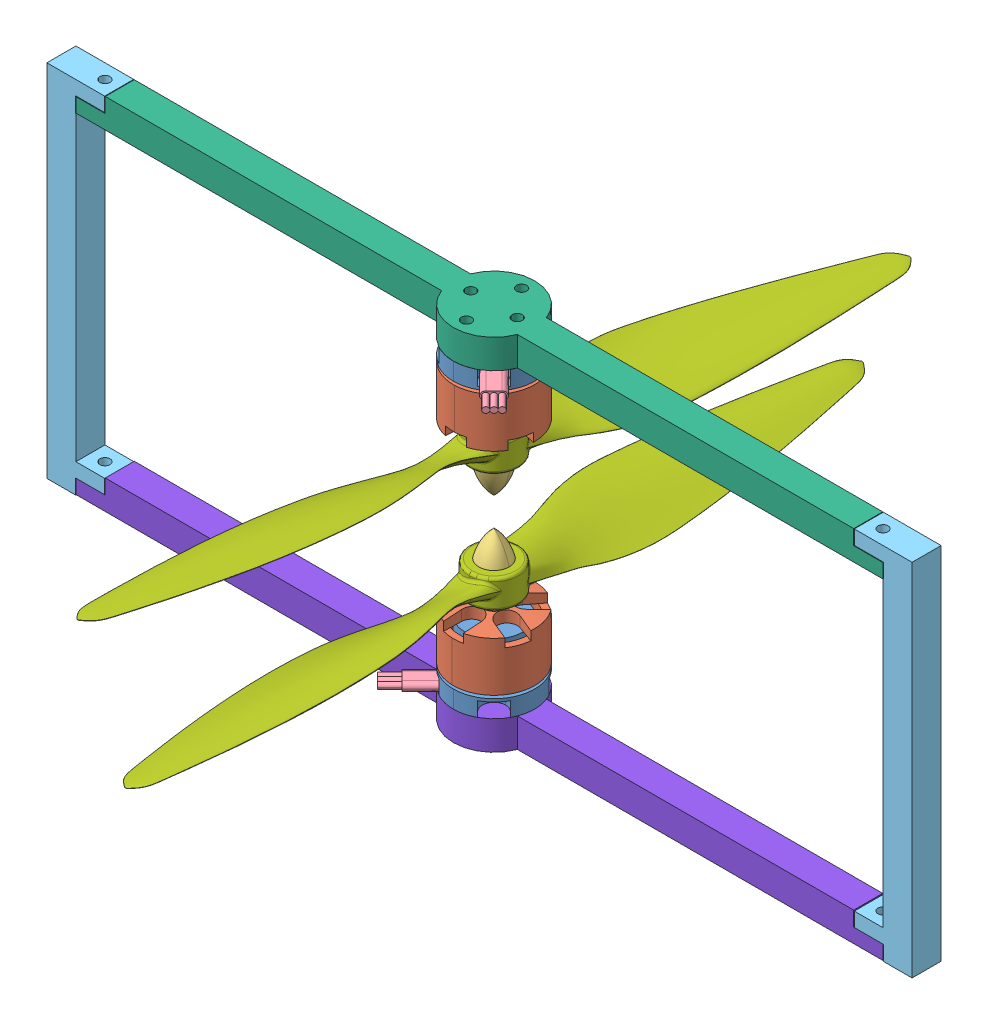
SolidWorks assembly Motor Mount Sub-Assembly, configuration Default. Lengths in mm.
Overall size (298 124 255.79).
16 component instances, 8 part files, 16 mates.
Components (placement in the parent):
- User Library-emaxmodel-mt2213.STEP-1: User Library-emaxmodel-mt2213.STEP [Default] at (3.5668 10.2 11.2261) size (36.98 47 36.98)
  - emaxmodel-mt2213-stator_По умолчанию.STEP-1: emaxmodel-mt2213-stator_По умолчанию.STEP [Default] at origin size (28 21 28)
  - emaxmodel-mt2213-rotor_По умолчанию.STEP-1: emaxmodel-mt2213-rotor_По умолчанию.STEP [Default] at (0 7 0) x (0.999557 0 0.02976) z (-0.02976 0 0.999557) size (28 32 28)
  - emaxmodel-mt2213-cone_По умолчанию.STEP-1: emaxmodel-mt2213-cone_По умолчанию.STEP [Default] at (0 32 0) size (12 15 13.86)
  - wires_По умолчанию.STEP-1: wires_По умолчанию.STEP [Default] at (-15.8508 1.5 15.8508) x (0.707107 0 0.707107) z (-0.707107 0 0.707107) size (7 3 19)
- Motor Mount Sides-1: Motor Mount Sides [Default] at (142.5668 0 16.2261) size (19.9 124 10)
- Motor Mount Sides-3: Motor Mount Sides [Default] at (-135.4332 0 6.2261) x (-1 0 0) z (0 0 -1) size (19.9 124 10)
- Motor Mount Lower-2: Motor Mount Lower [Default] at (3.5668 114 11.2261) size (277.8 10 28)
- Propeller 10x45.step-1: Propeller 10x45.step [Default] at (3.5668 43.2 11.2261) size (28.85 11.2 254.24)
- User Library-emaxmodel-mt2213.STEP-2: User Library-emaxmodel-mt2213.STEP [Default] at (3.5668 114 11.2261) x (-1 0 0) z (0 0 1) size (36.98 47 36.98)
  - emaxmodel-mt2213-stator_По умолчанию.STEP-1: emaxmodel-mt2213-stator_По умолчанию.STEP [Default] at origin size (28 21 28)
  - emaxmodel-mt2213-rotor_По умолчанию.STEP-1: emaxmodel-mt2213-rotor_По умолчанию.STEP [Default] at (0 7 0) x (0.999557 0 0.02976) z (-0.02976 0 0.999557) size (28 32 28)
  - emaxmodel-mt2213-cone_По умолчанию.STEP-1: emaxmodel-mt2213-cone_По умолчанию.STEP [Default] at (0 32 0) size (12 15 13.86)
  - wires_По умолчанию.STEP-1: wires_По умолчанию.STEP [Default] at (-15.8508 1.5 15.8508) x (0.707107 0 0.707107) z (-0.707107 0 0.707107) size (7 3 19)
- Propeller 10x45.step-2: Propeller 10x45.step [Default] at (3.5668 84 11.2261) x (-0.990503 0 -0.137494) z (-0.137494 0 0.990503) size (28.85 11.2 254.24)
- Motor Mount Upper-3: Motor Mount Upper [Default] at (3.5668 0.2 11.2261) size (277.8 10 28)
Mates (geometry in assembly coordinates):
- Concentric5: concentric anti-aligned: cylinder of Motor Mount Sides-1 through (137.5668 124 11.2261) axis (0 -1 0) radius 1.75; cylinder of Motor Mount Lower-2 through (137.5668 108.9 11.2261) axis (0 1 0) radius 1.75
- Concentric6: concentric anti-aligned: cylinder of Motor Mount Sides-3 through (-130.4332 124 11.2261) axis (0 -1 0) radius 1.75; cylinder of Motor Mount Lower-2 through (-130.4332 108.9 11.2261) axis (0 1 0) radius 1.75
- Distance3: distance = 0.2 mm anti-aligned: plane of Motor Mount Lower-2 through (-135.3332 118.9 25.2261) normal (0 1 0); plane of Motor Mount Sides-3 through (-125.5332 119.1 16.2261) normal (0 -1 0)
- Concentric7: concentric anti-aligned: cylinder of User Library-emaxmodel-mt2213.STEP-1/emaxmodel-mt2213-rotor_По умолчанию.STEP-1 through (3.5668 62.021 11.2261) axis (0 -1 0) radius 3; cylinder of Propeller 10x45.step-1 through (3.5668 51.021 11.2261) axis (0 1 0) radius 3
- Coincident7: coincident anti-aligned: plane of User Library-emaxmodel-mt2213.STEP-1/emaxmodel-mt2213-rotor_По умолчанию.STEP-1 through (3.5668 51.021 11.2261) normal (0 1 0); plane of Propeller 10x45.step-1 through (3.5668 51.021 11.2261) normal (0 -1 0)
- Concentric10: concentric anti-aligned: cylinder of User Library-emaxmodel-mt2213.STEP-2/emaxmodel-mt2213-rotor_По умолчанию.STEP-1 through (3.5668 75 11.2261) axis (0 1 0) radius 3; cylinder of Propeller 10x45.step-2 through (3.5668 89 11.2261) axis (0 -1 0) radius 3
- Coincident9: coincident anti-aligned: plane of User Library-emaxmodel-mt2213.STEP-2/emaxmodel-mt2213-rotor_По умолчанию.STEP-1 through (3.5668 89 11.2261) normal (0 -1 0); plane of Propeller 10x45.step-2 through (3.5668 89 11.2261) normal (0 1 0)
- Concentric11: concentric aligned: cylinder of Motor Mount Lower-2 through (11.5668 114 11.2261) axis (0 1 0) radius 1.75; cylinder of User Library-emaxmodel-mt2213.STEP-2/emaxmodel-mt2213-stator_По умолчанию.STEP-1 through (11.5668 109 11.2261) axis (0 1 0) radius 1
- Concentric12: concentric aligned: cylinder of Motor Mount Lower-2 through (3.5668 114 20.7261) axis (0 1 0) radius 1.75; cylinder of User Library-emaxmodel-mt2213.STEP-2/emaxmodel-mt2213-stator_По умолчанию.STEP-1 through (3.5668 109 20.7261) axis (0 1 0) radius 1
- Coincident10: coincident anti-aligned: plane of Motor Mount Lower-2 through (3.5668 114 11.2261) normal (0 -1 0); plane of User Library-emaxmodel-mt2213.STEP-2/emaxmodel-mt2213-stator_По умолчанию.STEP-1 through (3.5668 114 11.2261) normal (0 1 0)
- Concentric13: concentric anti-aligned: cylinder of Motor Mount Sides-3 through (-130.4332 124 11.2261) axis (0 -1 0) radius 1.75; cylinder of Motor Mount Upper-3 through (-130.4332 -4.9 11.2261) axis (0 1 0) radius 1.75
- Concentric14: concentric anti-aligned: cylinder of Motor Mount Sides-1 through (137.5668 124 11.2261) axis (0 -1 0) radius 1.75; cylinder of Motor Mount Upper-3 through (137.5668 -4.9 11.2261) axis (0 1 0) radius 1.75
- Concentric15: concentric anti-aligned: cylinder of User Library-emaxmodel-mt2213.STEP-1/emaxmodel-mt2213-stator_По умолчанию.STEP-1 through (3.5668 28.021 20.7261) axis (0 -1 0) radius 1; cylinder of Motor Mount Upper-3 through (3.5668 0.2 20.7261) axis (0 1 0) radius 1.75
- Concentric16: concentric anti-aligned: cylinder of User Library-emaxmodel-mt2213.STEP-1/emaxmodel-mt2213-stator_По умолчанию.STEP-1 through (-4.4332 28.021 11.2261) axis (0 -1 0) radius 1; cylinder of Motor Mount Upper-3 through (-4.4332 0.2 11.2261) axis (0 1 0) radius 1.75
- Coincident11: coincident anti-aligned: plane of Motor Mount Sides-3 through (-125.5332 5.1 16.2261) normal (0 -1 0); plane of Motor Mount Upper-3 through (-135.3332 5.1 25.2261) normal (0 1 0)
- Coincident12: coincident anti-aligned: plane of User Library-emaxmodel-mt2213.STEP-1/emaxmodel-mt2213-stator_По умолчанию.STEP-1 through (3.5668 10.2 11.2261) normal (0 -1 0); plane of Motor Mount Upper-3 through (3.5668 10.2 11.2261) normal (0 1 0)
